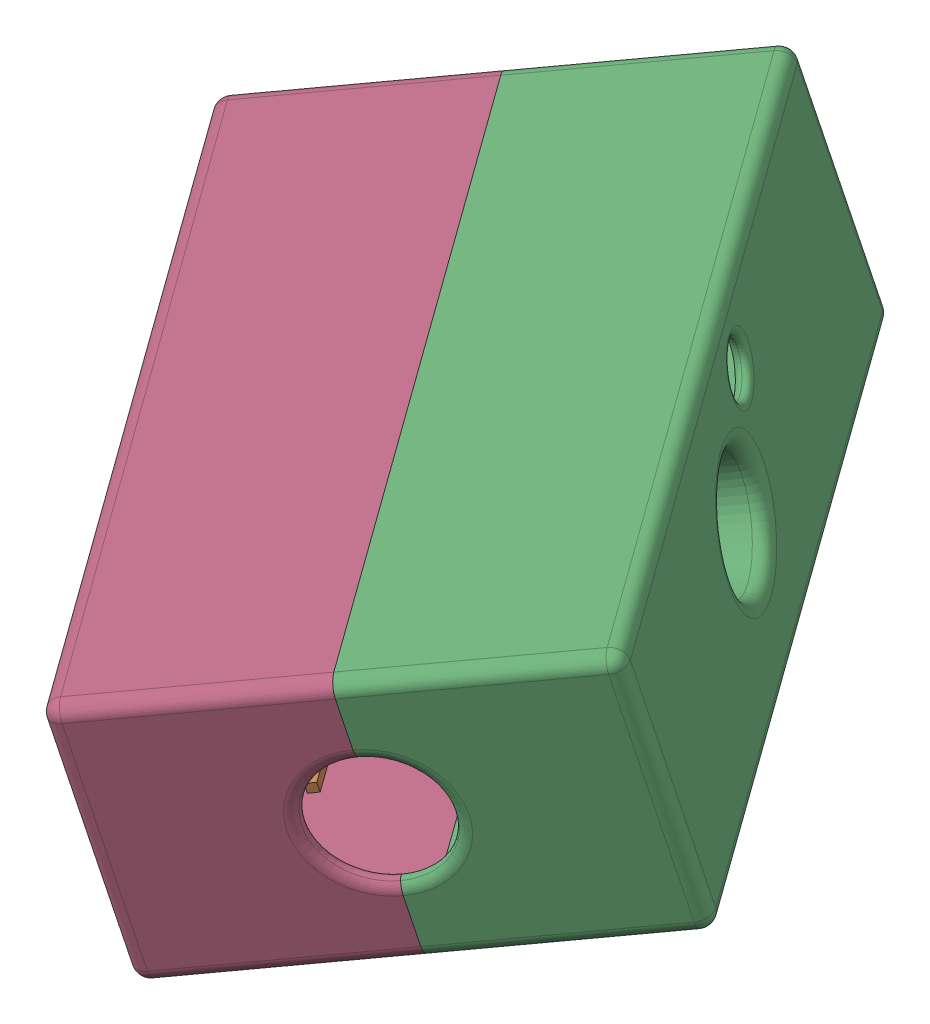
SolidWorks assembly Montagem Suporte Sensores, configuration Valor predeterminado. Lengths in mm.
Overall size (57.02 31.24 63.12).
4 component instances, 3 part files, 9 mates.
Components (placement in the parent):
- EXA212-1: EXA212 [Valor predeterminado] at (-7.4191 -1.7886 -10.4957) x (-0.563833 0.100633 -0.819735) z (0.812344 0.246597 -0.528477) size (44.9 15.1 14.02)
- EXA213-1: EXA213 [Valor predeterminado] at (-8.8813 -2.2325 -9.5444) x (-0.563833 0.100633 -0.819735) z (-0.812344 -0.246597 0.528477) size (44.72 15.1 14.02)
- EXA200-3: EXA200 [Valor predeterminado] at (6.3342 1.278 -14.6044) x (0.563833 -0.100633 0.819735) z (-0.812344 -0.246597 0.528477) size (50 19 16)
- EXA200-4: EXA200 [Valor predeterminado] at (-18.0361 -6.1199 1.2499) x (0.563833 -0.100633 0.819735) z (0.812344 0.246597 -0.528477) size (50 19 16)
Mates (geometry in assembly coordinates):
- Concêntrico1: concentric aligned: cylinder of EXA212-1 through (-1.6725 -1.9679 -5.836) axis (-0.812344 -0.246597 0.528477) radius 2.103; cylinder of EXA200-3 through (11.8124 2.1256 -14.6087) axis (-0.812344 -0.246597 0.528477) radius 2.05
- Paralelo1: parallel aligned: line of EXA212-1 through (3.2893 4.8105 2.1154) axis (-0.563833 0.100633 -0.819735); line of EXA200-3 through (8.0218 4.8537 13.9516) axis (-0.563833 0.100633 -0.819735)
- Coincidente1: coincident anti-aligned: plane of EXA212-1 through (-0.3727 -1.5733 -6.6816) normal (0.812344 0.246597 -0.528477); plane of EXA200-3 through (-0.3727 -1.5733 -6.6816) normal (-0.812344 -0.246597 0.528477)
- Concêntrico2: concentric anti-aligned: circle of EXA213-1; cylinder of EXA200-4 through (-18.3755 -7.0383 5.0303) axis (0.812344 0.246597 -0.528477) radius 2.05
- Paralelo2: parallel aligned: line of EXA213-1 through (-21.9542 6.59 -22.6843) axis (0.563833 -0.100633 0.819735); line of EXA200-4 through (-20.7981 9.1511 -24.2534) axis (0.563833 -0.100633 0.819735)
- Coincidente2: coincident anti-aligned: plane of EXA213-1 through (-6.1903 -3.3393 -2.8969) normal (-0.812344 -0.246597 0.528477); plane of EXA200-4 through (-6.1903 -3.3393 -2.8969) normal (0.812344 0.246597 -0.528477)
- Concêntrico3: concentric anti-aligned: cylinder of EXA212-1 through (-1.6725 -1.9679 -5.836) axis (-0.812344 -0.246597 0.528477) radius 2.103; cylinder of EXA213-1 through (-4.8905 -2.9448 -3.7424) axis (0.812344 0.246597 -0.528477) radius 2.103
- Paralelo3: parallel anti-aligned: line of EXA200-3 through (8.0218 4.8537 13.9516) axis (-0.563833 0.100633 -0.819735); line of EXA200-4 through (-20.7981 9.1511 -24.2534) axis (0.563833 -0.100633 0.819735)
- Coincidente3: coincident anti-aligned: plane of EXA200-3 through (-4.0951 -1.8879 -7.8196) normal (-0.812344 -0.246597 0.528477); plane of EXA200-4 through (-5.8509 -2.4209 -6.6773) normal (0.812344 0.246597 -0.528477)
